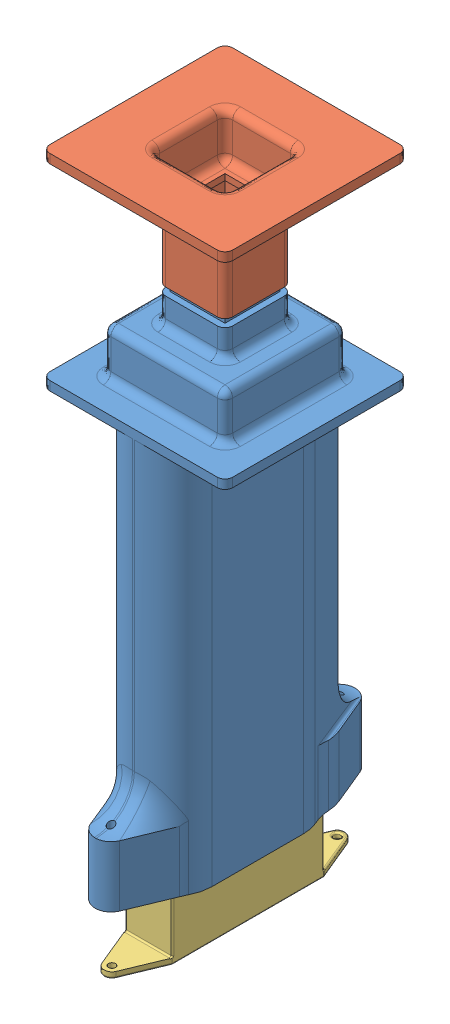
SolidWorks assembly Assem1, configuration Default. Lengths in mm.
Overall size (60 215.82 85.29).
3 component instances, 3 part files, 5 mates.
Components (placement in the parent):
- Standoff Half-1: Standoff Half [Default] at (14.8586 19.4324 58.103) size (60 165 85.29)
- Standoff Half2-1: Standoff Half2 [Default] at (14.8586 86.9923 58.103) x (1 0 0) z (0 0 -1) size (60 38 60)
- Glider Release-1: Glider Release [Default] at (14.6056 -177.1051 57.995) x (0 0 -1) z (-1 0 0) size (78.99 27.94 15.55)
Mates (geometry in assembly coordinates):
- Coincident1: coincident anti-aligned: plane of Standoff Half-1 through (5.8586 46.4324 49.103) normal (0 0 -1); plane of Standoff Half2-1 through (5.8586 69.9923 49.103) normal (0 0 1)
- Coincident2: coincident anti-aligned: plane of Standoff Half-1 through (23.8586 46.4324 67.103) normal (1 0 0); plane of Standoff Half2-1 through (23.8586 69.9923 49.103) normal (-1 0 0)
- Coincident3: coincident anti-aligned: plane of Standoff Half-1 through (14.8586 46.4324 58.103) normal (0 1 0); plane of Standoff Half2-1 through (14.8586 46.4324 58.103) normal (0 -1 0)
- Coincident4: coincident anti-aligned: plane of Standoff Half-1 through (6.8586 -81.5676 83.103) normal (1 0 0); plane of Glider Release-1 through (6.8586 -177.1051 57.995) normal (-1 0 0)
- Coincident5: coincident anti-aligned: plane of Standoff Half-1 through (6.8586 -81.5676 33.103) normal (0 0 1); plane of Glider Release-1 through (6.8586 -100.8924 33.103) normal (0 0 -1)
